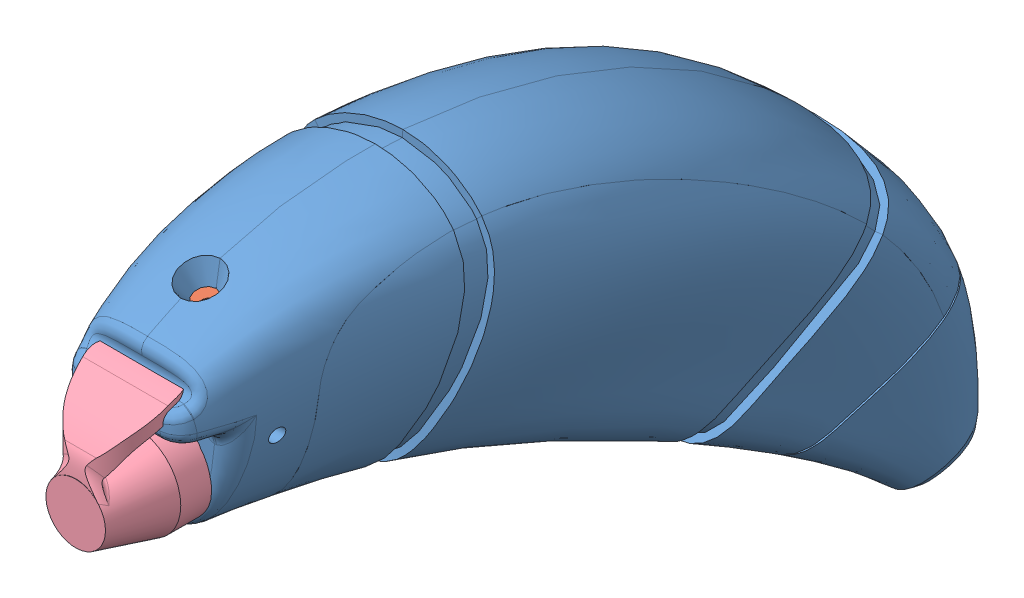
SolidWorks assembly Assem1, configuration Default. Lengths in mm.
Overall size (12.28 24.94 39.25).
4 component instances, 4 part files, 7 mates.
Components (placement in the parent):
- DJB_Rev2_Case_3-1: DJB_Rev2_Case_3 [Default] at (-38.7106 -11.0313 7.5909) size (12.28 24.94 37.15)
- djb_v2_flex-1: djb_v2_flex [Default] at (-39.3399 11.6969 24.394) x (-0.000331 -0.173648 -0.984808) z (0.999998 -0.001906 0) size (29.71 8.74 2.75)
- djb_v2_rigid-1: djb_v2_rigid [Default] at (-38.9982 9.9399 28.7416) x (0 0 1) z (-0.999998 0.001906 0) size (24.08 14.43 3.16)
- CS44 Long Connector-1: CS44 Long Connector [Default] at (-38.7106 11.0891 30.5096) x (-1 0 0) z (0 0 -1) size (4.3 6.42 9.03)
Mates (geometry in assembly coordinates):
- Parallel1: parallel: line of djb_v2_flex-1 through (-39.5587 12.3156 22.6603) axis (0.000331 0.173648 0.984808); line of djb_v2_rigid-1 through (-39.893 12.7091 25.3352) axis (-0.000331 -0.173648 -0.984808)
- Parallel3: parallel: plane of djb_v2_flex-1 through (-39.5402 11.5551 25.8914) normal (-0.999998 0.001906 0); plane of djb_v2_rigid-1 through (-39.8924 12.9986 25.962) normal (-0.999998 0.001906 0)
- Coincident9: coincident: plane of djb_v2_flex-1 through (-39.5377 12.8614 25.8134) normal (0.000331 0.173648 0.984808); plane of djb_v2_rigid-1 through (-39.7125 12.9062 25.8056) normal (-0.000331 -0.173648 -0.984808)
- Coincident10: coincident: plane of djb_v2_flex-1 through (-39.335 14.2467 25.5691) normal (0.999998 -0.001906 0); plane of djb_v2_rigid-1 through (-39.3377 12.8584 25.8467) normal (-0.999998 0.001906 0)
- Coincident15: coincident: point of DJB_Rev2_Case_3-1; moEndPointRef_w of djb_v2_rigid-1
- Concentric7: concentric: cylinder of djb_v2_rigid-1 through (-38.7106 11.0891 29.7617) axis (0 0 1) radius 1.05; cylinder of CS44 Long Connector-1 through (-38.7106 11.0891 29.0096) axis (0 0 1) radius 1
- Parallel4: parallel: line of DJB_Rev2_Case_3-1 through (-36.9606 15.6765 28.8499) axis (1 0 0); line of CS44 Long Connector-1 through (-40.5772 15.0129 35.6749) axis (1 0 0)
